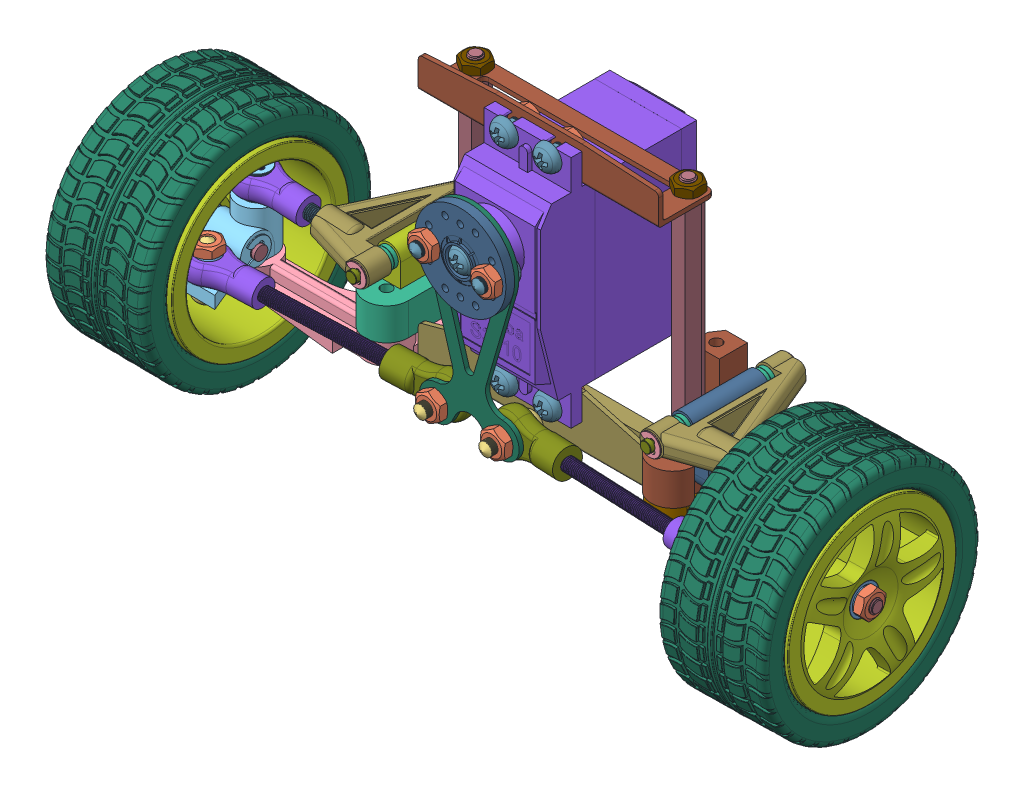
SolidWorks assembly 转向机构, configuration 默认. Lengths in mm.
Overall size (173.65 86.22 65.74).
107 component instances, 37 part files, 14 mates.
Components (placement in the parent):
- 底盘-1: 底盘 [默认] at (9.4104 -39.3367 102.1559) x (1 0 0.000031) z (0 1 0) size (141 210 8.86) (hidden)
- 右前轮-1: 右前轮 [默认] at (78.7056 -37.9301 -139.4207) x (0.000031 0 -1) z (0.051127 -0.998692 0.000001) size (61.14 64.35 61.71) (flexible)
  - 半球型活动头-1: 半球型活动头 [默认] at (-77.7494 -7.564 -22.0484) x (0.472633 0.879261 0.059309) z (0.881177 -0.472437 -0.018165) size (5.8 4.8 5.8)
  - 沉头螺钉-M3-1: 沉头螺钉-M3 [GB_WOOD_SCREWS_TYPE135 3X8-C] at (-71.5787 -28.9461 -13.2908) x (0 -0.998692 -0.051127) z (0.300279 -0.048767 0.952604) size (8.5 6 6)
  - 弹簧-1: 弹簧 [默认] at (-76.6558 -6.4137 1.0793) x (-0.017992 0.997998 0.060626) z (-0.012048 -0.060847 0.998074) size (4.64 4.5 4.5)
  - 挡圈-M2.5-1: 挡圈-M2.5 [默认] at (-50.8787 -34.3142 -21.8764) x (0 -0.001803 0.999998) z (-1 0 0) size (5 4.5 0.3)
  - 挡圈-M3-1: 挡圈-M3 [默认] at (-76.3474 -4.856 -24.4714) x (-0.001175 0.998147 0.060838) z (-0.012048 -0.060847 0.998074) size (6 5.32 0.3)
  - 垫片-M3-1: 垫片-M3 [默认] at (-56.8787 -34.3142 -21.8764) x (0 -0.001803 0.999998) z (-1 0 0) size (4.5 4.5 1)
  - 轮毂-前轮-1: 轮毂-前轮 [默认] at (-79.9223 13.5325 -10.3684) x (-0.984519 0.040406 -0.170554) z (-0.172628 -0.055066 0.983447) size (40 26.36 40)
  - 前拉杆球头-1: 前拉杆球头 [默认] at (-76.3787 -5.0142 -21.8764) x (0 1 0) z (1 0 0) size (16.5 5.82 9)
  - 前轮悬挂固定座-右-1: 前轮悬挂固定座-右 [默认] at (-76.5787 -36.0054 -6.4427) x (1 0 0) z (0 -0.051127 0.998692) size (28.6 39.6 7.36)
  - 前轮悬挂连接件上半部分-右-1: 前轮悬挂连接件上半部分-右 [默认] at (-57.9787 -34.3142 -21.8764) x (0 -0.051127 0.998692) z (-1 0 0) size (14.6 8.6 17.2)
  - 前轮悬挂连接件下半部分-右-1: 前轮悬挂连接件下半部分-右 [默认] at (-57.5787 -35.8623 -9.2391) x (0 -0.998692 -0.051127) z (0 0.051127 -0.998692) size (16 29 16.6)
  - 前轮悬挂支撑臂-1: 前轮悬挂支撑臂 [默认] at (-76.3787 -34.3142 -24.1764) size (31.32 16.5 6)
  - 前轮轴-1: 前轮轴 [默认] at (-80.5535 -7.2189 -11.6412) x (0.431488 0.042144 -0.901134) z (-0.030346 -0.997665 -0.061189) size (4.6 4.19 25.74)
  - 丝杆-1: 丝杆 [默认] at (-76.3787 -23.5142 -21.8764) x (0.836211 0 -0.548408) z (0 -1 0) size (3.03 3.46 12.09)
  - 橡胶胎-1: 橡胶胎 [默认] at (-79.9162 13.7321 -10.3562) x (-0.984519 0.040406 -0.170554) z (-0.172628 -0.055066 0.983447) size (52.2 24.12 52.2)
  - 悬挂销钉-M2.5-1: 悬挂销钉-M2.5 [默认] at (-49.8787 -34.3142 -21.8764) x (0 0.772819 0.634626) z (-1 0 0) size (2.5 2.5 34)
  - 悬挂销钉-M3-1: 悬挂销钉-M3 [默认] at (-76.3378 -4.8073 -25.2699) x (-0.017992 0.997998 0.060626) z (-0.012048 -0.060847 0.998074) size (3 3 27.5)
  - 沉头螺钉-M3-2: 沉头螺钉-M3 [GB_WOOD_SCREWS_TYPE135 3X8-C] at (-61.5787 -28.9461 -13.2908) x (0 -0.998692 -0.051127) z (0.300279 -0.048767 0.952604) size (8.5 6 6)
  - 垫片-M3-2: 垫片-M3 [默认] at (-55.8787 -34.3142 -21.8764) x (0 -0.001803 0.999998) z (-1 0 0) size (4.5 4.5 1)
  - 垫片-M3-3: 垫片-M3 [默认] at (-77.1787 -34.3142 -21.8764) x (0 0.001803 -0.999998) z (1 0 0) size (4.5 4.5 1)
  - 垫片-M3-4: 垫片-M3 [默认] at (-76.1787 -34.3142 -21.8764) x (0 0.001803 -0.999998) z (1 0 0) size (4.5 4.5 1)
  - 挡圈-M2.5-2: 挡圈-M2.5 [默认] at (-82.8787 -34.3142 -21.8764) x (0 0.001803 -0.999998) z (1 0 0) size (5 4.5 0.3)
  - 挡圈-M3-2: 挡圈-M3 [默认] at (-76.6558 -6.4137 1.0793) x (-0.017992 0.997998 0.060626) z (-0.012048 -0.060847 0.998074) size (6 5.32 0.3)
  - 半球型活动头-2: 半球型活动头 [默认] at (-73.6806 -6.1249 -5.2796) x (-0.999348 0.034698 -0.009948) z (-0.034026 -0.997544 -0.061226) size (5.8 4.8 5.8)
  - 转向摇臂-右-1: 转向摇臂-右 [默认] at (-76.5378 -5.8173 -8.7019) x (0.030346 0.997665 0.061189) z (0.012048 0.060847 -0.998074) size (14.2 22.2 10)
  - 垫片-M3-5: 垫片-M3 [默认] at (-76.4076 -5.1602 -19.4811) x (-0.00325 0.998144 0.060812) z (-0.012048 -0.060847 0.998074) size (4.5 4.5 1)
  - 垫片-M3-6: 垫片-M3 [默认] at (-76.5378 -5.8173 -8.7019) x (-0.000213 0.998147 0.060849) z (-0.012048 -0.060847 0.998074) size (4.5 4.5 1)
  - 深沟轴承-M7-1: 深沟轴承-M7 [Rolling bearings 618-3 GB 276-94] at (-80.25 2.7577 -11.0293) x (-0.030346 -0.997665 -0.061189) z (-0.946 0.0089 0.324043) size (2 7 7)
  - 深沟轴承-M7-2: 深沟轴承-M7 [Rolling bearings 618-3 GB 276-94] at (-80.0072 10.7391 -10.5398) x (0.030346 0.997665 0.061189) z (-0.172628 -0.055066 0.983447) size (2 7 7)
  - 挡圈-M3-3: 挡圈-M3 [默认] at (-80.6415 -10.1121 -11.8186) x (0.978686 -0.017218 -0.204638) z (0.030346 0.997665 0.061189) size (6 5.32 0.3)
  - 六角螺母-M3-1: 六角螺母-M3 [GB_FASTENER_NUT_SNAB1 M3-C] at (-79.9041 14.1311 -10.3317) x (0.978686 -0.017218 -0.204638) z (0.030346 0.997665 0.061189) size (6.35 5.5 2.4)
  - 半球型活动头-3: 半球型活动头 [默认] at (-94.2846 -8.8904 -14.3135) x (0.999909 -0.006818 0.011655) z (0.006095 0.998124 0.060924) size (5.8 4.8 5.8)
  - 六角螺母-M3-2: 六角螺母-M3 [GB_FASTENER_NUT_SNAB1 M3-C] at (-91.356 -8.7642 -16.675) x (0.999927 -0.001125 0.012002) z (-0.012048 -0.060847 0.998074) size (6.35 5.5 2.4)
  - 前拉杆球头-2: 前拉杆球头 [默认] at (-91.3849 -8.9102 -14.2797) x (-0.080424 0.99668 0.0127) z (-0.996721 -0.080527 0.007864) size (16.5 5.82 9)
  - 十字半圆头长螺钉-M3-1: 十字半圆头长螺钉-M3 [GB_WOOD_SCREWS_TYPE136 M3X8-N] at (-91.4761 -9.3708 -6.7242) x (0.012048 0.060847 -0.998074) z (0.99283 0.117985 0.019178) size (12.81 5.8 5.8)
- 左前轮-1: 左前轮 [默认] at (-64.199 -40.5593 -107.6556) x (0.025755 -0.999668 0.000001) z (-0.000031 0 1) size (63.82 63.37 63.94) (flexible)
  - 前轮悬挂固定座-左-1: 前轮悬挂固定座-左 [默认] at (-4.1748 40.7369 44.8092) x (0 0 -1) z (-0.999668 0.025755 0) size (28.6 39.6 7.4)
  - 前轮悬挂支撑臂-1: 前轮悬挂支撑臂 [默认] at (-19.3996 40.1041 44.6092) x (0 0 -1) z (-0.996802 0.079912 0) size (31.32 16.5 6)
  - 转向摇臂-左-1: 转向摇臂-左 [默认] at (-10.8363 10.8664 44.7682) x (0.016039 0.999637 0.021663) z (-0.999795 0.016302 -0.012048) size (14.2 22.2 10.13)
  - 沉头螺钉-M3-1: 沉头螺钉-M3 [GB_WOOD_SCREWS_TYPE135 3X8-C] at (-13.5443 34.2761 39.8092) x (0.025755 0.999668 0) z (-0.463299 0.011936 0.886121) size (8.5 6 6)
  - 沉头螺钉-M3-2: 沉头螺钉-M3 [GB_WOOD_SCREWS_TYPE135 3X8-C] at (-13.5443 34.2761 29.8092) x (0.025755 0.999668 0) z (0 0 1) size (8.5 6 6)
  - 悬挂销钉-M2.5-1: 悬挂销钉-M2.5 [默认] at (-21.6922 40.2879 18.1092) x (0.999999 0.001056 0) z (0 0 1) size (2.5 2.5 34)
  - 挡圈-M2.5-1: 挡圈-M2.5 [默认] at (-21.6922 40.2879 19.4092) x (-0.923323 -0.384024 0) z (0 0 -1) size (5 4.5 0.3)
  - 挡圈-M2.5-2: 挡圈-M2.5 [默认] at (-21.6922 40.2879 50.8092) x (0.999999 0.001056 0) z (0 0 1) size (5 4.5 0.3)
  - 垫片-M3-2: 垫片-M3 [默认] at (-21.6922 40.2879 43.4092) x (0.999999 0.001056 0) z (0 0 1) size (4.5 4.5 1)
  - 垫片-M3-3: 垫片-M3 [默认] at (-21.6922 40.2879 44.4092) x (0.880813 -0.473464 0) z (0 0 1) size (4.5 4.5 1)
  - 垫片-M3-4: 垫片-M3 [默认] at (-21.6922 40.2879 25.1092) x (0.999999 0.001056 0) z (0 0 1) size (4.5 4.5 1)
  - 悬挂销钉-M3-1: 悬挂销钉-M3 [默认] at (-27.5329 11.1387 44.567) x (-0.007065 0.276875 0.96088) z (0.999795 -0.016302 0.012048) size (3 3 27.5)
  - 前拉杆球头-1: 前拉杆球头 [默认] at (-24.0336 11.0816 44.6092) x (-0.079912 -0.996802 0) z (0 0 1) size (16.5 5.82 9)
  - 半球型活动头-1: 半球型活动头 [默认] at (-24.0567 11.7503 47.4309) x (0.007965 -0.230598 -0.973017) z (-0.018641 -0.972913 0.230421) size (5.8 4.8 5.8)
  - 挡圈-M3-1: 挡圈-M3 [默认] at (-26.7331 11.1256 44.5767) x (0.019643 0.925978 -0.377065) z (0.999795 -0.016302 0.012048) size (6 5.32 0.3)
  - 挡圈-M3-2: 挡圈-M3 [默认] at (-1.1383 10.7083 44.8851) x (0.019537 0.616464 -0.78714) z (0.999795 -0.016302 0.012048) size (6 5.32 0.3)
  - 垫片-M3-5: 垫片-M3 [默认] at (-20.6343 11.0262 44.6501) x (-0.007721 0.243288 0.969923) z (-0.999795 0.016302 -0.012048) size (4.5 4.5 1)
  - 半球型活动头-2: 半球型活动头 [默认] at (-7.4714 10.8468 47.7088) x (0.011848 -0.012342 -0.999854) z (0.016449 0.999791 -0.012146) size (5.8 4.8 5.8)
  - 垫片-M3-6: 垫片-M3 [默认] at (-9.8366 10.8501 44.7803) x (-0.014725 -0.175589 0.984353) z (-0.999795 0.016302 -0.012048) size (4.5 4.5 1)
  - 前轮轴-1: 前轮轴 [默认] at (-13.6581 12.5256 48.7701) x (-0.912192 0.005757 0.409724) z (0.016039 0.999637 0.021663) size (4.6 4.19 25.74)
  - 挡圈-M3-3: 挡圈-M3 [默认] at (-13.6164 15.1246 48.8264) x (0.998969 -0.0151 -0.042805) z (0.016039 0.999637 0.021663) size (6 5.32 0.3)
  - 轮毂-前轮-1: 轮毂-前轮 [默认] at (-13.9917 -8.2669 48.3195) x (0.9691 -0.020875 0.245783) z (-0.246146 -0.017051 0.969083) size (40 26.36 40)
  - 橡胶胎-1: 橡胶胎 [默认] at (-13.9949 -8.4668 48.3152) x (0.9691 -0.020875 0.245783) z (-0.246146 -0.017051 0.969083) size (52.2 24.12 52.2)
  - 深沟轴承-M7-1: 深沟轴承-M7 [Rolling bearings 618-3 GB 276-94] at (-13.8185 2.5292 48.5535) x (-0.016039 -0.999637 -0.021663) z (0.150274 -0.02383 0.988357) size (2 7 7)
  - 深沟轴承-M7-2: 深沟轴承-M7 [Rolling bearings 618-3 GB 276-94] at (-13.9468 -5.4679 48.3802) x (0.016039 0.999637 0.021663) z (-0.246146 -0.017051 0.969083) size (2 7 7)
  - 六角螺母-M3-2: 六角螺母-M3 [GB_FASTENER_NUT_SNAB1 M3-C] at (-13.9628 -6.4675 48.3585) x (0.998969 -0.0151 -0.042805) z (0.016039 0.999637 0.021663) size (6.35 5.5 2.4)
  - 丝杆-1: 丝杆 [默认] at (-22.3555 32.0144 44.6092) x (0.307615 -0.024661 0.951191) z (0.079912 0.996802 0) size (3.03 3.46 12.09)
  - 弹簧-1: 弹簧 [默认] at (-1.1383 10.7083 44.8851) x (0.019 0.960768 -0.276703) z (0.999795 -0.016302 0.012048) size (4.64 4.5 4.5)
  - 前轮悬挂连接件下半部分-左-2: 前轮悬挂连接件下半部分-左 [默认] at (-8.9732 40.8605 44.8092) x (0.025755 0.999668 0) z (-0.999668 0.025755 0) size (16 29 16.6)
  - 前轮悬挂连接件上半部分-左-3: 前轮悬挂连接件上半部分-左 [默认] at (-21.6922 40.2879 26.2092) x (0.999668 -0.025755 0) z (0 0 1) size (14.6 8.6 17.2)
  - 垫片-M3-7: 垫片-M3 [默认] at (-21.6922 40.2879 24.1092) x (1 -0.000397 0) z (0 0 1) size (4.5 4.5 1)
  - 前拉杆球头-2: 前拉杆球头 [默认] at (-16.1565 14.514 59.5851) x (-0.066221 -0.994605 0.079846) z (-0.020321 0.081349 0.996478) size (16.5 5.82 9)
  - 半球型活动头-3: 半球型活动头 [默认] at (-16.1096 17.4134 59.6205) x (-0.016155 -0.999795 -0.01221) z (-0.012245 -0.012013 0.999853) size (5.8 4.8 5.8)
  - 六角螺母-M3-3: 六角螺母-M3 [GB_FASTENER_NUT_SNAB1 M3-C] at (-18.556 14.5531 59.5562) x (0.01231 0.016069 -0.999795) z (0.999795 -0.016302 0.012048) size (6.35 5.5 2.4)
  - 十字半圆头长螺钉-M3-1: 十字半圆头长螺钉-M3 [GB_WOOD_SCREWS_TYPE136 M3X8-N] at (-8.588 14.3906 59.6763) x (-0.999795 0.016302 -0.012048) z (0.012049 0.95587 0.293544) size (12.81 5.8 5.8)
- 舵机装配-1: 舵机装配 [默认] at (-2.4778 -56.8707 -75.6063) x (0.000031 0 -1) z (0 1 0) size (50 105.1 61.5) (flexible)
  - 舵机-1: 舵机 [默认] at (-7.7618 -11.8937 34.529) size (40 20.22 54.02)
  - 舵机齿轮-1: 舵机齿轮 [默认] at (-25.7618 -11.8937 63.729) x (0 0 -1) z (1 0 0) size (5.77 5.77 4)
  - 舵机摆臂连接件-1: 舵机摆臂连接件 [默认] at (-23.2618 -11.8937 63.729) x (0 0.00203 0.999998) z (-1 0 0) size (21 21 6.01)
  - 舵机支架-上-1: 舵机支架-上 [默认] at (2.2382 -11.8937 75.034) x (0 1 0) z (0 0 1) size (55.4 13 8)
  - 舵机支架-下-1: 舵机支架-下 [默认] at (2.2382 -11.8937 21.534) x (0 1 0) z (0 0 1) size (55.4 13 11.75)
  - 铜柱-舵机-1: 铜柱-舵机 [默认] at (-0.7618 -36.3937 22.534) x (0.003094 0.999995 0) z (0 0 1) size (5.75 5.22 56.58)
  - 铜柱-舵机-2: 铜柱-舵机 [默认] at (-0.7618 12.6063 22.534) x (0.89164 0.452745 0) z (0 0 1) size (5.75 5.22 56.58)
  - 十字半圆头螺钉-M3-1: 十字半圆头螺钉-M3 [GB_WOOD_SCREWS_TYPE136 M3X8-N] at (-15.6318 -6.8937 79.284) x (1 0 0) z (0 0 1) size (9.31 5.8 5.8)
  - 十字半圆头螺钉-M3-3: 十字半圆头螺钉-M3 [GB_WOOD_SCREWS_TYPE136 M3X8-N] at (-15.6318 -16.8937 79.284) x (1 0 0) z (0 0 1) size (9.31 5.8 5.8)
  - 十字半圆头螺钉-M3-4: 十字半圆头螺钉-M3 [GB_WOOD_SCREWS_TYPE136 M3X8-N] at (-15.6318 -6.8937 29.784) x (1 0 0) z (0 0 1) size (9.31 5.8 5.8)
  - 十字半圆头螺钉-M3-5: 十字半圆头螺钉-M3 [GB_WOOD_SCREWS_TYPE136 M3X8-N] at (-15.6318 -16.8937 29.784) x (1 0 0) z (0 0 1) size (9.31 5.8 5.8)
  - 六角螺母-M3-4: 六角螺母-M3 [GB_FASTENER_NUT_SNAB1 M3-C] at (-7.3618 -6.8937 29.784) x (0 0 -1) z (1 0 0) size (6.35 5.5 2.4)
  - 六角螺母-M3-5: 六角螺母-M3 [GB_FASTENER_NUT_SNAB1 M3-C] at (-7.3618 -16.8937 29.784) x (0 0 -1) z (1 0 0) size (6.35 5.5 2.4)
  - 六角螺母-M3-6: 六角螺母-M3 [GB_FASTENER_NUT_SNAB1 M3-C] at (-7.3618 -16.8937 79.284) x (0 0 -1) z (1 0 0) size (6.35 5.5 2.4)
  - 六角螺母-M3-7: 六角螺母-M3 [GB_FASTENER_NUT_SNAB1 M3-C] at (-7.3618 -6.8937 79.284) x (0 0 -1) z (1 0 0) size (6.35 5.5 2.4)
  - 舵机拉杆-1: 舵机拉杆 [默认] at (-26.7618 -11.9606 30.7291) x (0 0.999998 -0.00203) z (1 0 0) size (23 47.5 1)
  - 十字半圆头螺钉-M3-8: 十字半圆头螺钉-M3 [GB_WOOD_SCREWS_TYPE136 M3X8-N] at (-30.1318 -11.8937 63.729) x (1 0 0) z (0 0 1) size (9.31 5.8 5.8)
  - 半球型活动头-1: 半球型活动头 [默认] at (-23.3618 -3.3533 28.0336) x (0 -0.38185 0.924224) z (0 0.924224 0.38185) size (5.8 4.8 5.8)
  - 舵机拉杆球头-1: 舵机拉杆球头 [默认] at (-23.3618 -4.4607 30.7138) x (0.079846 -0.995981 -0.040583) z (0.008505 0.041392 -0.999107) size (17.5 6.4 9.4)
  - 半球型活动头-2: 半球型活动头 [默认] at (-23.3618 -22.3606 30.7443) x (0 1 0) z (0 0 1) size (5.8 4.8 5.8)
  - 舵机拉杆球头-2: 舵机拉杆球头 [默认] at (-23.3618 -19.4606 30.7443) x (0.080424 0.996026 -0.038273) z (0.005998 0.037913 0.999263) size (17.5 6.4 9.4)
  - 丝杆-舵机-1: 丝杆-舵机 [默认] at (-26.9389 40.1593 32.532) x (-0.566301 -0.078829 0.82042) z (-0.079846 0.995981 0.040583) size (3.06 3.46 35.46)
  - 丝杆-舵机-2: 丝杆-舵机 [默认] at (-24.15 -29.2217 31.1194) x (0.857658 -0.049584 0.511824) z (0.080424 0.996026 -0.038273) size (3.06 3.46 35.46)
  - 六角螺母-M3-黄色-1: 六角螺母-M3-黄色 [GB_FASTENER_NUT_SNAB1 M3-C] at (-0.7618 12.6063 78.434) x (1 0.000031 0) z (0 0 1) size (6.35 5.5 2.4)
  - 六角螺母-M3-黄色-2: 六角螺母-M3-黄色 [GB_FASTENER_NUT_SNAB1 M3-C] at (-0.7618 -36.3937 78.434) x (1 0.000031 0) z (0 0 1) size (6.35 5.5 2.4)
  - 十字半圆头螺钉-M3-12: 十字半圆头螺钉-M3 [GB_WOOD_SCREWS_TYPE136 M3X8-N] at (-23.3918 -4.6437 63.7143) x (-1 0 0) z (0 0.924224 0.38185) size (9.31 5.8 5.8)
  - 六角螺母-M3-14: 六角螺母-M3 [GB_FASTENER_NUT_SNAB1 M3-C] at (-31.1618 -4.6437 63.7143) x (0 0 1) z (-1 0 0) size (6.35 5.5 2.4)
  - 十字半圆头长螺钉-M3-3: 十字半圆头长螺钉-M3 [GB_WOOD_SCREWS_TYPE136 M3X8-N] at (-18.5918 -4.4607 30.7138) x (-1 0 0) z (0 0.924224 0.38185) size (12.81 5.8 5.8)
  - 十字半圆头长螺钉-M3-4: 十字半圆头长螺钉-M3 [GB_WOOD_SCREWS_TYPE136 M3X8-N] at (-18.5918 -19.4606 30.7443) x (-1 0 0) z (0 0.924224 0.38185) size (12.81 5.8 5.8)
  - 六角螺母-M3-16: 六角螺母-M3 [GB_FASTENER_NUT_SNAB1 M3-C] at (-29.1618 -4.4607 30.7138) x (0 0 1) z (-1 0 0) size (6.35 5.5 2.4)
  - 六角螺母-M3-17: 六角螺母-M3 [GB_FASTENER_NUT_SNAB1 M3-C] at (-29.1618 -19.4606 30.7443) x (0 0 1) z (-1 0 0) size (6.35 5.5 2.4)
  - 十字半圆头螺钉-M3-14: 十字半圆头螺钉-M3 [GB_WOOD_SCREWS_TYPE136 M3X8-N] at (-23.3918 -19.1436 63.7437) x (-1 0 0) z (0 0.924224 0.38185) size (9.31 5.8 5.8)
  - 六角螺母-M3-18: 六角螺母-M3 [GB_FASTENER_NUT_SNAB1 M3-C] at (-31.1618 -19.1436 63.7437) x (0 0 1) z (-1 0 0) size (6.35 5.5 2.4)
Mates (geometry in assembly coordinates):
- 重合120: coincident anti-aligned: plane of 底盘-1 through (-55.5891 -35.3367 86.1539) normal (0 1 0); plane of 左前轮-1/前轮悬挂固定座-左-1 through (-23.5845 -35.3367 -62.8452) normal (0 -1 0)
- 同心109: concentric aligned: cylinder of 底盘-1 through (-23.5845 -39.3367 -62.8452) axis (0 -1 0) radius 1.7; cylinder of 左前轮-1/前轮悬挂固定座-左-1 through (-23.5845 -33.3367 -62.8452) axis (0 -1 0) radius 1.5
- 同心110: concentric aligned: cylinder of 底盘-1 through (-23.5839 -39.3367 -81.8452) axis (0 -1 0) radius 1.7; cylinder of 左前轮-1/前轮悬挂固定座-左-1 through (-23.5839 -33.3367 -81.8452) axis (0 -1 0) radius 1.5
- 重合121: coincident anti-aligned: plane of 底盘-1 through (-55.5891 -35.3367 86.1539) normal (0 1 0); plane of 右前轮-1/前轮悬挂固定座-右-1 through (42.4155 -35.3367 -62.8431) normal (0 -1 0)
- 同心111: concentric anti-aligned: cylinder of 底盘-1 through (42.4155 -39.3367 -62.8431) axis (0 -1 0) radius 1.7; cylinder of 右前轮-1/前轮悬挂固定座-右-1 through (42.4155 -35.3367 -62.8431) axis (0 1 0) radius 1.5
- 同心112: concentric anti-aligned: cylinder of 底盘-1 through (42.4161 -39.3367 -81.8431) axis (0 -1 0) radius 1.7; cylinder of 右前轮-1/前轮悬挂固定座-右-1 through (42.4161 -35.3367 -81.8431) axis (0 1 0) radius 1.5
- 平行1: parallel anti-aligned: plane of 底盘-1 through (-55.5891 -35.3367 86.1539) normal (0 1 0); plane of 舵机装配-1/舵机-1 through (-0.5837 -22.3417 -87.8445) normal (0 -1 0)
- 平行2: parallel anti-aligned: plane of 底盘-1 through (-34.9276 -35.3367 -107.8455) normal (0.000031 0 -1); plane of 舵机装配-1/舵机-1 through (-0.5948 -17.3148 -54.8445) normal (-0.000031 0 1)
- 重合1442: coincident anti-aligned: plane of 底盘-1 through (-55.5891 -35.3367 86.1539) normal (0 1 0); plane of 舵机装配-1/舵机支架-下-1 through (9.416 -35.3367 -77.8441) normal (0 -1 0)
- 同心1413: concentric anti-aligned: cylinder of 左前轮-1/前拉杆球头-2 through (-38.156 -24.5214 -49.0278) axis (0.995983 -0.040583 -0.079815) radius 1.25; cylinder of 舵机装配-1/丝杆-舵机-1 through (-7.7785 -25.7591 -51.4622) axis (-0.995983 0.040583 0.079815) radius 1.5
- 同心1414: concentric aligned: cylinder of 右前轮-1/前拉杆球头-2 through (57.1219 -24.5839 -49.0016) axis (-0.996023 -0.038274 -0.080454) radius 1.25; cylinder of 舵机装配-1/丝杆-舵机-2 through (61.604 -24.4117 -48.6396) axis (-0.996023 -0.038274 -0.080454) radius 1.5
- 距离2: distance = 4.5 mm anti-aligned: plane of 舵机装配-1/丝杆-舵机-1 through (-42.6379 -24.3387 -48.6687) normal (-0.995983 0.040583 0.079815); plane of 左前轮-1/前拉杆球头-2 through (-38.156 -24.5214 -49.0278) normal (0.995983 -0.040583 -0.079815)
- 距离3: distance = 4.5 mm anti-aligned: plane of 右前轮-1/前拉杆球头-2 through (57.1219 -24.5839 -49.0016) normal (-0.996023 -0.038274 -0.080454); plane of 舵机装配-1/丝杆-舵机-2 through (61.604 -24.4117 -48.6396) normal (0.996023 0.038274 0.080454)
- 同心1415: concentric aligned: cylinder of 底盘-1 through (33.9159 -39.3367 -74.8434) axis (0 -1 0) radius 1.7; cylinder of 舵机装配-1/铜柱-舵机-1 through (33.9159 -34.3367 -74.8434) axis (0 -1 0) radius 1.25
